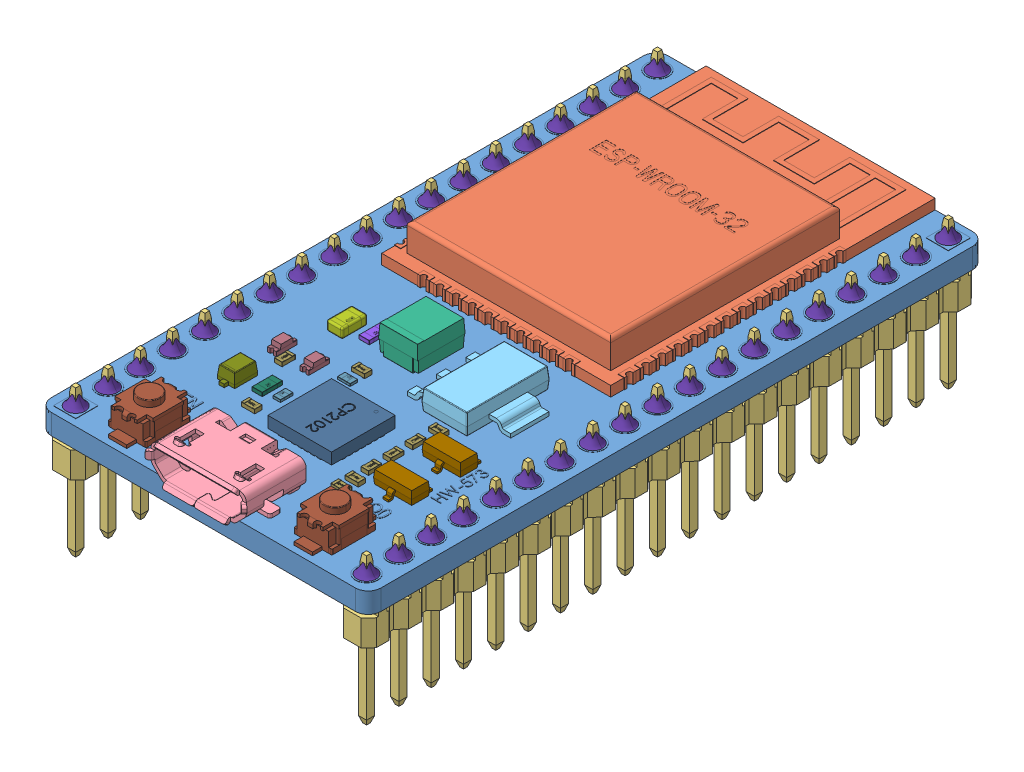
SolidWorks assembly ESP32S Dev Board 0.9inch width ASSY.STEP, configuration Default. Lengths in mm.
Overall size (25.91 13.14 49.31).
67 component instances, 17 part files, 0 mates.
Components (placement in the parent):
- ESP32S HW-573 PCB.STEP-1: ESP32S HW-573 PCB.STEP [Default] at origin size (25.91 1.64 48.51)
- ESP-WROOM-32.STEP-1: ESP-WROOM-32.STEP [Default] at (0 1.565 -11.507) x (-1 0 0) z (0 1 0) size (18.07 25.54 3.04)
- Male Header 19P 100 Pitch.STEP-1: Male Header 19P 100 Pitch.STEP [Default] at (11.43 -0.5 -0.005) x (0 0 1) z (0 -1 0) size (47.96 2.54 11.54)
- Male Header 19P 100 Pitch.STEP-2: Male Header 19P 100 Pitch.STEP [Default] at (-11.43 -0.5 -0.005) x (0 0 1) z (0 -1 0) size (47.96 2.54 11.54)
- micro_usb_47346-0001.STEP-1: micro_usb_47346-0001.STEP [Default] at (0 2.825 22.277) size (7.98 2.94 5.43)
- CircuitWorks-SOT-223.STEP-1: CircuitWorks-SOT-223.STEP [Default] at (4.374 2.38 6.453) x (0 0 -1) z (1 0 0) size (6.5 1.68 6.96)
- Pol Cap SMD 3528 H2mm.STEP-1: Pol Cap SMD 3528 H2mm.STEP [Default] at (-1.5369 1.6 5.5499) x (-1 0 0) z (0 0 -1) size (3.07 2.13 3.73)
- 0805 SMD Capacitor.STEP-1: 0805 SMD Capacitor.STEP [Default] at (-6.069 1.6 6.903) x (0 0 1) z (-1 0 0) size (2 0.78 1.25)
- 0603 SMD Resistor.STEP-1: 0603 SMD Resistor.STEP [Default] at (-4.444 1.6 6.383) x (0 0 1) z (-1 0 0) size (1.6 0.3 0.8)
- SOT-23.STEP-1: SOT-23.STEP [Default] at (7.1934 2.15 12.053) size (3 1.1 2.5)
- QFN28_5X5.STEP-1: QFN28_5X5.STEP [Default] at (0.202 1.6 14.385) x (0 0 1) z (0 1 0) size (5 5 0.95)
- SOT-23.STEP-2: SOT-23.STEP [Default] at (7.1934 2.15 15.8743) size (3 1.1 2.5)
- Tact Switch SMD Tab 4mmx3mm.STEP-1: Tact Switch SMD Tab 4mmx3mm.STEP [Default] at (-7.25 1.65 21.257) x (0 0 1) z (-1 0 0) size (5 2.3 3)
- Tact Switch SMD Tab 4mmx3mm.STEP-2: Tact Switch SMD Tab 4mmx3mm.STEP [Default] at (7.35 1.65 21.257) x (0 0 1) z (-1 0 0) size (5 2.3 3)
- 0402 SMD Resistor___ _________.STEP-1: 0402 SMD Resistor___ _________.STEP [Default] at (4.684 1.58 10.4458) size (1.04 0.34 0.6)
- 0402 SMD Resistor___ _________.STEP-2: 0402 SMD Resistor___ _________.STEP [Default] at (4.684 1.58 18.0958) size (1.04 0.34 0.6)
- 0402 SMD Resistor___ _________.STEP-3: 0402 SMD Resistor___ _________.STEP [Default] at (4.684 1.58 16.9958) size (1.04 0.34 0.6)
- 0402 SMD Resistor___ _________.STEP-4: 0402 SMD Resistor___ _________.STEP [Default] at (4.514 1.58 15.5758) x (0 0 1) z (-1 0 0) size (1.04 0.34 0.6)
- 0402 SMD Resistor___ _________.STEP-5: 0402 SMD Resistor___ _________.STEP [Default] at (4.514 1.58 12.0958) x (0 0 1) z (-1 0 0) size (1.04 0.34 0.6)
- 0402 SMD Resistor___ _________.STEP-6: 0402 SMD Resistor___ _________.STEP [Default] at (4.514 1.58 13.8358) x (0 0 1) z (-1 0 0) size (1.04 0.34 0.6)
- LED SMD0603.STEP-1: LED SMD0603.STEP [Default] at (-4.6812 1.5952 10.2006) x (1 0 0) z (0 1 0) size (0.72 1.65 0.68)
- LED SMD0603.STEP-2: LED SMD0603.STEP [Default] at (-7.2362 1.5952 10.2006) x (1 0 0) z (0 1 0) size (0.72 1.65 0.68)
- 0402 SMD Resistor___ _________.STEP-7: 0402 SMD Resistor___ _________.STEP [Default] at (-6.279 1.58 11.573) x (0 0 1) z (-1 0 0) size (1.04 0.34 0.6)
- 0402 SMD Capacitor.STEP-1: 0402 SMD Capacitor.STEP [Default] at (-2.454 1.6 10.4668) size (1 0.2 0.6)
- 0402 SMD Resistor___ _________.STEP-8: 0402 SMD Resistor___ _________.STEP [Default] at (-2.434 1.6 9.3668) size (1.04 0.34 0.6)
- 0603 SMD Capacitor.STEP-1: 0603 SMD Capacitor.STEP [Default] at (-5.12 1.6 14.117) x (0 0 1) z (-1 0 0) size (1.6 0.3 0.8)
- 0402 SMD Resistor___ _________.STEP-9: 0402 SMD Resistor___ _________.STEP [Default] at (-4.37 1.58 16.077) size (1.04 0.34 0.6)
- 0402 SMD Capacitor.STEP-2: 0402 SMD Capacitor.STEP [Default] at (-3.9 1.6 14.097) x (0 0 -1) z (1 0 0) size (1 0.2 0.6)
- SOD323F-1.STEP-1: SOD323F-1.STEP [Default] at (-7.029 1.6 14.543) x (0 0 -1) z (0 1 0) size (2.5 1.35 1)
- Pin Solder Joint.STEP-1: Pin Solder Joint.STEP [Default] at (11.43 1.62 22.86) size (1.5 1.1 1.5)
- Pin Solder Joint.STEP-2: Pin Solder Joint.STEP [Default] at (-11.43 1.62 22.86) size (1.5 1.1 1.5)
- Pin Solder Joint.STEP-3: Pin Solder Joint.STEP [Default] at (11.43 1.62 20.32) size (1.5 1.1 1.5)
- Pin Solder Joint.STEP-4: Pin Solder Joint.STEP [Default] at (-11.43 1.62 20.32) size (1.5 1.1 1.5)
- Pin Solder Joint.STEP-5: Pin Solder Joint.STEP [Default] at (11.43 1.62 17.78) size (1.5 1.1 1.5)
- Pin Solder Joint.STEP-6: Pin Solder Joint.STEP [Default] at (-11.43 1.62 17.78) size (1.5 1.1 1.5)
- Pin Solder Joint.STEP-7: Pin Solder Joint.STEP [Default] at (11.43 1.62 15.24) size (1.5 1.1 1.5)
- Pin Solder Joint.STEP-8: Pin Solder Joint.STEP [Default] at (-11.43 1.62 15.24) size (1.5 1.1 1.5)
- Pin Solder Joint.STEP-9: Pin Solder Joint.STEP [Default] at (11.43 1.62 12.7) size (1.5 1.1 1.5)
- Pin Solder Joint.STEP-10: Pin Solder Joint.STEP [Default] at (-11.43 1.62 12.7) size (1.5 1.1 1.5)
- Pin Solder Joint.STEP-11: Pin Solder Joint.STEP [Default] at (11.43 1.62 10.16) size (1.5 1.1 1.5)
- Pin Solder Joint.STEP-12: Pin Solder Joint.STEP [Default] at (-11.43 1.62 10.16) size (1.5 1.1 1.5)
- Pin Solder Joint.STEP-13: Pin Solder Joint.STEP [Default] at (11.43 1.62 7.62) size (1.5 1.1 1.5)
- Pin Solder Joint.STEP-14: Pin Solder Joint.STEP [Default] at (-11.43 1.62 7.62) size (1.5 1.1 1.5)
- Pin Solder Joint.STEP-15: Pin Solder Joint.STEP [Default] at (11.43 1.62 5.08) size (1.5 1.1 1.5)
- Pin Solder Joint.STEP-16: Pin Solder Joint.STEP [Default] at (-11.43 1.62 5.08) size (1.5 1.1 1.5)
- Pin Solder Joint.STEP-17: Pin Solder Joint.STEP [Default] at (11.43 1.62 2.54) size (1.5 1.1 1.5)
- Pin Solder Joint.STEP-18: Pin Solder Joint.STEP [Default] at (-11.43 1.62 2.54) size (1.5 1.1 1.5)
- Pin Solder Joint.STEP-19: Pin Solder Joint.STEP [Default] at (11.43 1.62 0) size (1.5 1.1 1.5)
- Pin Solder Joint.STEP-20: Pin Solder Joint.STEP [Default] at (-11.43 1.62 0) size (1.5 1.1 1.5)
- Pin Solder Joint.STEP-21: Pin Solder Joint.STEP [Default] at (11.43 1.62 -2.54) size (1.5 1.1 1.5)
- Pin Solder Joint.STEP-22: Pin Solder Joint.STEP [Default] at (-11.43 1.62 -2.54) size (1.5 1.1 1.5)
- Pin Solder Joint.STEP-23: Pin Solder Joint.STEP [Default] at (11.43 1.62 -5.08) size (1.5 1.1 1.5)
- Pin Solder Joint.STEP-24: Pin Solder Joint.STEP [Default] at (-11.43 1.62 -5.08) size (1.5 1.1 1.5)
- Pin Solder Joint.STEP-25: Pin Solder Joint.STEP [Default] at (11.43 1.62 -7.62) size (1.5 1.1 1.5)
- Pin Solder Joint.STEP-26: Pin Solder Joint.STEP [Default] at (-11.43 1.62 -7.62) size (1.5 1.1 1.5)
- Pin Solder Joint.STEP-27: Pin Solder Joint.STEP [Default] at (11.43 1.62 -10.16) size (1.5 1.1 1.5)
- Pin Solder Joint.STEP-28: Pin Solder Joint.STEP [Default] at (-11.43 1.62 -10.16) size (1.5 1.1 1.5)
- Pin Solder Joint.STEP-29: Pin Solder Joint.STEP [Default] at (11.43 1.62 -12.7) size (1.5 1.1 1.5)
- Pin Solder Joint.STEP-30: Pin Solder Joint.STEP [Default] at (-11.43 1.62 -12.7) size (1.5 1.1 1.5)
- Pin Solder Joint.STEP-31: Pin Solder Joint.STEP [Default] at (11.43 1.62 -15.24) size (1.5 1.1 1.5)
- Pin Solder Joint.STEP-32: Pin Solder Joint.STEP [Default] at (-11.43 1.62 -15.24) size (1.5 1.1 1.5)
- Pin Solder Joint.STEP-33: Pin Solder Joint.STEP [Default] at (11.43 1.62 -17.78) size (1.5 1.1 1.5)
- Pin Solder Joint.STEP-34: Pin Solder Joint.STEP [Default] at (-11.43 1.62 -17.78) size (1.5 1.1 1.5)
- Pin Solder Joint.STEP-35: Pin Solder Joint.STEP [Default] at (11.43 1.62 -20.32) size (1.5 1.1 1.5)
- Pin Solder Joint.STEP-36: Pin Solder Joint.STEP [Default] at (-11.43 1.62 -20.32) size (1.5 1.1 1.5)
- Pin Solder Joint.STEP-37: Pin Solder Joint.STEP [Default] at (11.43 1.62 -22.86) size (1.5 1.1 1.5)
- Pin Solder Joint.STEP-38: Pin Solder Joint.STEP [Default] at (-11.43 1.62 -22.86) size (1.5 1.1 1.5)
